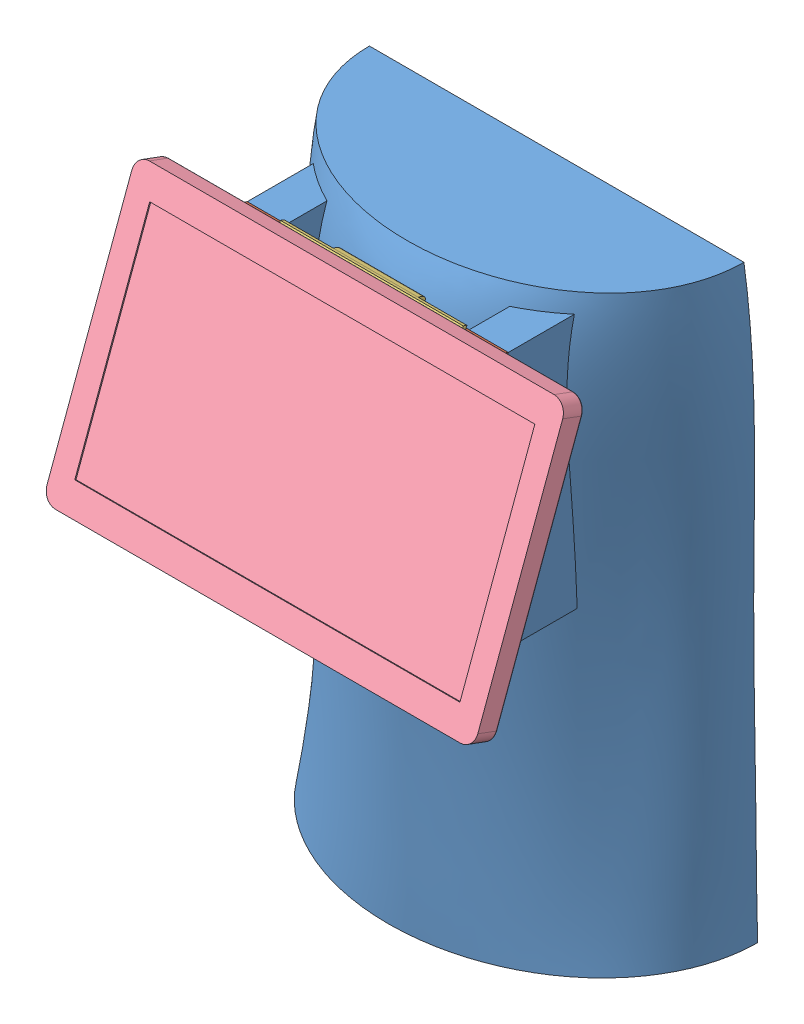
SolidWorks assembly Assem1, configuration Default. Lengths in mm.
Overall size (351.52 448.71 241.02).
4 component instances, 4 part files, 9 mates.
Components (placement in the parent):
- Base_upper_front-1: Base_upper_front [Default] at (140.7972 168.6809 403.0002) size (351.52 448.71 221.76)
- acrylic sheet-1: acrylic sheet [Default] at (40.7972 333.6159 612.6072) x (1 0 0) z (0 0.345755 0.938325) size (200 210 3)
- bracket_display1-1: bracket_display1 [Default] at (140.7972 435.9923 578.0807) x (0 0.938325 -0.345755) z (0 -0.345755 -0.938325) size (180 150 15.98)
- 13.3 inch Display-1: 13.3 inch Display [Default] at (140.7972 437.0295 580.8957) x (0 0.938325 -0.345755) z (0 0.345755 0.938325) size (208 330 16)
Mates (geometry in assembly coordinates):
- Coincident1: coincident anti-aligned: plane of Base_upper_front-1 through (240.7972 530.6642 539.9988) normal (0 0.345755 0.938325); plane of acrylic sheet-1 through (40.7972 333.6159 612.6072) normal (0 -0.345755 -0.938325)
- Coincident2: coincident aligned: plane of Base_upper_front-1 through (240.7972 530.6642 145.3011) normal (1 0 0); plane of acrylic sheet-1 through (240.7972 334.6532 615.4222) normal (1 0 0)
- Concentric1: concentric anti-aligned: cylinder of Base_upper_front-1 through (225.7972 501.4771 547.5564) axis (0 0.345755 0.938325) radius 2; cylinder of acrylic sheet-1 through (225.7972 537.0899 644.2039) axis (0 -0.345755 -0.938325) radius 2
- Coincident8: coincident anti-aligned: plane of acrylic sheet-1 through (40.7972 334.6532 615.4222) normal (0 0.345755 0.938325); plane of bracket_display1-1 through (140.7972 435.9923 578.0807) normal (0 -0.345755 -0.938325)
- Coincident10: coincident anti-aligned: plane of acrylic sheet-1 through (40.7972 531.7014 542.8137) normal (0 0.938325 -0.345755); plane of bracket_display1-1 through (140.7972 531.7014 542.8137) normal (0 -0.938325 0.345755)
- Coincident11: coincident anti-aligned: plane of bracket_display1-1 through (140.7972 437.0295 580.8957) normal (0 0.345755 0.938325); plane of 13.3 inch Display-1 through (295.7972 525.2321 548.3947) normal (0 -0.345755 -0.938325)
- Width2: width anti-aligned: plane of bracket_display1-1 through (70.7972 435.9923 578.0807) normal (-1 0 0); plane of Base_upper_front-1 through (210.7972 435.9923 578.0807) normal (1 0 0); plane of bracket_display1-1 through (240.7972 530.6642 145.3011) normal (1 0 0); plane of Base_upper_front-1 through (40.7972 530.6642 145.3011) normal (-1 0 0)
- Concentric3: concentric aligned: cylinder of bracket_display1-1 through (90.7972 489.8236 579.5595) axis (0 -0.345755 -0.938325) radius 2.5; cylinder of 13.3 inch Display-1 through (90.7972 487.4033 572.9912) axis (0 -0.345755 -0.938325) radius 2.5
- Concentric4: concentric aligned: cylinder of bracket_display1-1 through (190.7972 395.9911 614.1349) axis (0 -0.345755 -0.938325) radius 2.5; cylinder of 13.3 inch Display-1 through (190.7972 393.5708 607.5667) axis (0 -0.345755 -0.938325) radius 2.5
